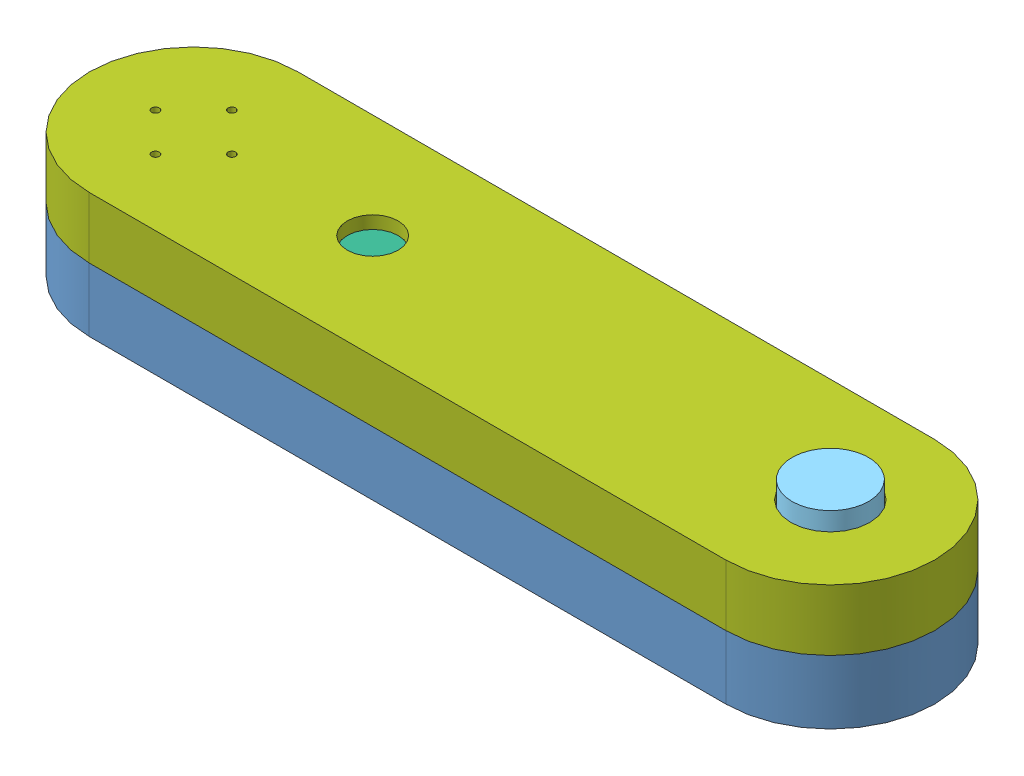
SolidWorks assembly upperlimbaseembly, configuration Default. Lengths in mm.
Overall size (332 62.9 82).
7 component instances, 7 part files, 15 mates.
Components (placement in the parent):
- upper limb-1: upper limb [Default] at (12.4618 156.9967 244.8744) size (332 25 82)
- MAD5008IPE-1: MAD5008IPE [Default] at (12.4618 156.9967 244.8744) size (56 29.3 56)
- W_61706_2RZ-1: W_61706_2RZ [Default] at (262.4618 159.9967 244.8744) x (0 -1 0) z (0 0 1) size (4 46.12 46.12)
- GT2 48T -1: GT2 48T  [Default] at (12.4618 182.7967 244.8747) x (0 0 1) z (0 1 0) size (32.6 32.6 10.1)
- GT2_80T-1: GT2_80T [Default] at (262.4618 191.4967 244.8744) x (-0.660602 0 0.750736) z (0 -1 0) size (55 55 62.9)
- combined pulley v2-1: combined pulley v2 [Default] at (69.8034 170.1382 246.9041) x (0.173679 0 -0.984802) z (0.984802 0 0.173679) size (55 19.9 55)
- upper limb cover-1: upper limb cover [Default] at (12.4618 195.9967 244.8744) x (1 0 0) z (0 0 -1) size (332 24 82)
Mates (geometry in assembly coordinates):
- Concentric1: concentric anti-aligned: cylinder of upper limb-1 through (12.4618 151.9967 229.8744) axis (0 1 0) radius 1.5; cylinder of MAD5008IPE-1 through (12.4618 159.9967 229.8744) axis (0 -1 0) radius 1.5
- Concentric2: concentric anti-aligned: cylinder of upper limb-1 through (12.4618 151.9967 259.8744) axis (0 1 0) radius 1.5; cylinder of MAD5008IPE-1 through (12.4618 159.9967 259.8744) axis (0 -1 0) radius 1.5
- Coincident1: coincident anti-aligned: plane of upper limb-1 through (12.4618 156.9967 244.8744) normal (0 1 0); plane of MAD5008IPE-1 through (12.4618 156.9967 244.8744) normal (0 -1 0)
- Concentric3: concentric anti-aligned: cylinder of upper limb-1 through (262.4618 155.9967 244.8744) axis (0 1 0) radius 18.5; cylinder of W_61706_2RZ-1 through (262.4618 109.9967 244.8744) axis (0 -1 0) radius 18.5
- Coincident2: coincident anti-aligned: plane of upper limb-1 through (262.4618 155.9967 244.8744) normal (0 1 0); plane of W_61706_2RZ-1 through (277.6618 155.9967 244.8744) normal (0 -1 0)
- Concentric4: concentric aligned: cylinder of MAD5008IPE-1 through (12.4618 186.2967 244.8744) axis (0 -1 0) radius 2; cylinder of GT2 48T -1 through (12.4618 192.8967 244.8744) axis (0 -1 0) radius 2
- Concentric5: concentric anti-aligned: cylinder of MAD5008IPE-1 through (19.9618 179.7967 244.8744) axis (0 1 0) radius 1.5; cylinder of GT2 48T -1 through (19.9618 192.8967 244.8744) axis (0 -1 0) radius 1.5
- Coincident3: coincident anti-aligned: plane of MAD5008IPE-1 through (12.4618 182.7967 244.8744) normal (0 1 0); plane of GT2 48T -1 through (12.4618 182.7967 244.8744) normal (0 -1 0)
- Coincident6: coincident aligned: plane of GT2 48T -1 through (12.4618 192.8967 244.8744) normal (0 1 0); plane of combined pulley v2-1 through (82.7618 192.8967 244.8744) normal (0 1 0)
- Coincident7: coincident aligned: plane of GT2_80T-1 through (262.4618 172.9967 244.8744) normal (0 -1 0); plane of combined pulley v2-1 through (82.7618 172.9967 244.8744) normal (0 -1 0)
- Concentric6: concentric anti-aligned: cylinder of W_61706_2RZ-1 through (262.4618 109.9967 244.8744) axis (0 -1 0) radius 18.5; cylinder of GT2_80T-1 through (262.4618 181.9967 244.8744) axis (0 1 0) radius 27.5
- Concentric7: concentric aligned: cylinder of upper limb-1 through (82.7618 151.9967 244.8744) axis (0 1 0) radius 10; cylinder of combined pulley v2-1 through (82.7618 191.3967 244.8744) axis (0 1 0) radius 27.5
- Concentric8: concentric aligned: cylinder of GT2_80T-1 through (262.4618 207.8967 244.8744) axis (0 -1 0) radius 15; cylinder of upper limb cover-1 through (262.4618 200.9967 244.8744) axis (0 -1 0) radius 15.5
- Concentric9: concentric anti-aligned: cylinder of combined pulley v2-1 through (82.7618 191.3967 244.8744) axis (0 1 0) radius 27.5; cylinder of upper limb cover-1 through (82.7618 200.9967 244.8744) axis (0 -1 0) radius 10
- Coincident8: coincident anti-aligned: plane of upper limb-1 through (12.4618 176.9967 244.8744) normal (0 1 0); plane of upper limb cover-1 through (12.4618 176.9967 244.8744) normal (0 -1 0)
